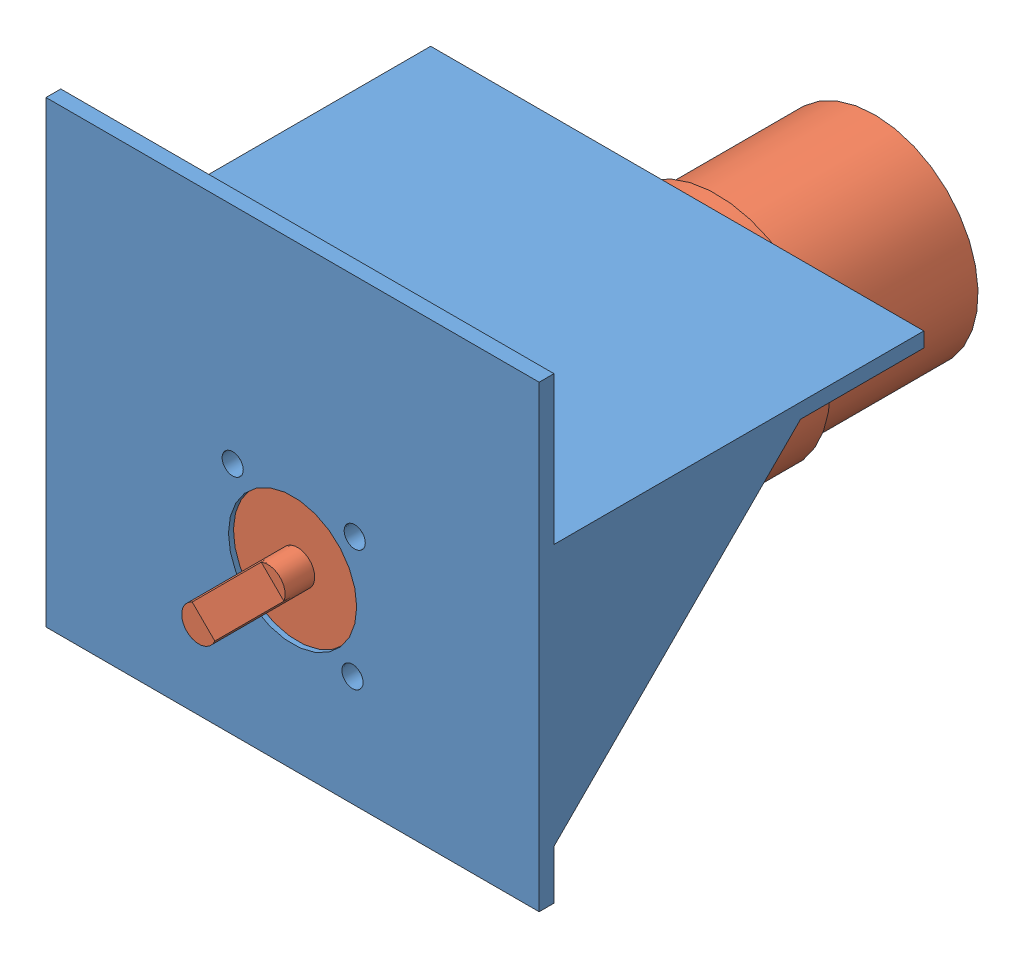
SolidWorks assembly Assem1, configuration Default. Lengths in mm.
Overall size (100 93 142).
2 component instances, 2 part files, 3 mates.
Components (placement in the parent):
- clamp-1: clamp [Default] at (9.7568 69.2379 79.7221) size (100 93 78)
- motor-1: motor [Default] at (9.7568 44.2379 2.2221) x (0.924315 -0.38163 0) z (-0.38163 -0.924315 0) size (46 142 46)
Mates (geometry in assembly coordinates):
- Parallel1: parallel aligned: plane of clamp-1 through (9.7568 69.2379 120.2221) normal (0 0 1); plane of motor-1 through (9.7568 44.2379 119.2221) normal (0 0 1)
- Coincident2: coincident anti-aligned: circle of clamp-1; circle of motor-1
- Coincident3: coincident anti-aligned: circle of clamp-1; circle of motor-1
